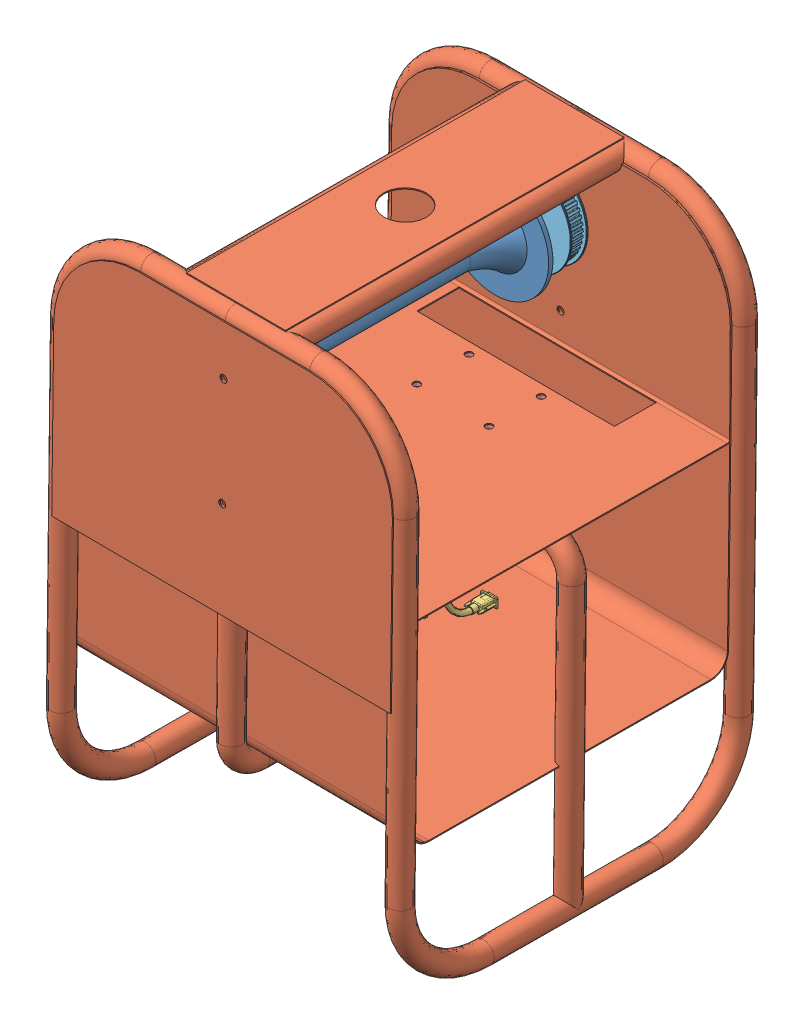
SolidWorks assembly Assem2c, configuration Default. Lengths in mm.
Overall size (326.74 509.34 328.95).
6 component instances, 6 part files, 11 mates.
Components (placement in the parent):
- mech for manipulator--1: mech for manipulator- [Default] at (-39.806 157.4104 77.9153) x (-0.943968 0.330031 -0.001958) z (0.000036 0.006038 0.999982) size (96.52 96.52 282.19)
- Robot_Chassis 1-1: Robot_Chassis 1 [Default] at (-40.8705 -18.8948 220.3334) x (0.000036 0.006038 0.999982) z (0.006038 0.999964 -0.006038) size (325.88 323.85 477.27)
- 23HS45-4204D-E1000-MC-1: 23HS45-4204D-E1000-MC [Default] at (-40.796 -6.4542 236.4495) x (-0.999982 0.006037 -0.000036) z (0 -0.006038 -0.999982) size (57.01 145.68 152.5)
- Part5-1: Part5 [Default] at (-0.507 40.5924 121.5634) x (-0.999982 0.006037 -0.000036) z (0 -0.006038 -0.999982) size (80 90 63.17)
- 3563N32_XL Series Lightweight Timing Belt Pulley-1: 3563N32_XL Series Lightweight Timing Belt Pulley [3563N32] at (-39.805 157.5811 106.197) x (-0.590425 -0.807077 0.004894) z (-0.000036 -0.006038 -0.999982) size (83.31 83.31 22.1)
- 3563N22_XL Series Lightweight Timing Belt Pulley-1: 3563N22_XL Series Lightweight Timing Belt Pulley [3563N22] at (-40.796 -7.2281 108.2629) x (0.907114 0.420877 -0.002541) z (0 -0.006038 -0.999982) size (44.45 44.45 22.1)
Mates (geometry in assembly coordinates):
- Coincident6: coincident anti-aligned: circle of mech for manipulator--1
- Parallel1: parallel anti-aligned: plane of 23HS45-4204D-E1000-MC-1 through (-69.1234 21.5346 123.2785) normal (0.006038 0.999964 -0.006038); plane of Part5-1 through (-80.5247 38.2627 181.5785) normal (-0.006038 -0.999964 0.006038)
- Parallel2: parallel anti-aligned: plane of 23HS45-4204D-E1000-MC-1 through (-40.796 -7.1461 121.8516) normal (0 -0.006038 -0.999982); plane of Part5-1 through (-0.507 40.5924 121.5634) normal (0 0.006038 0.999982)
- Tangent1: tangent anti-aligned: cylinder of 23HS45-4204D-E1000-MC-1 through (-64.2232 16.575 123.3084) axis (0 -0.006038 -0.999982) radius 2.55; plane of Part5-1 through (-66.728 24.043 118.4882) normal (0.999982 -0.006037 0.000036)
- Coincident7: coincident anti-aligned: plane of 23HS45-4204D-E1000-MC-1 through (-40.796 -7.1461 121.8516) normal (0 -0.006038 -0.999982); plane of Part5-1 through (-0.507 40.5924 121.5634) normal (0 0.006038 0.999982)
- Concentric2: concentric aligned: cylinder of mech for manipulator--1 through (-39.7957 159.1141 360.1041) axis (-0.000036 -0.006038 -0.999982) radius 6.35; cylinder of 3563N32_XL Series Lightweight Timing Belt Pulley-1 through (-39.8054 157.5144 95.1482) axis (-0.000036 -0.006038 -0.999982) radius 6.0058
- Concentric3: concentric anti-aligned: cylinder of 23HS45-4204D-E1000-MC-1 through (-40.796 -7.2632 102.452) axis (0 0.006038 0.999982) radius 4; cylinder of 3563N22_XL Series Lightweight Timing Belt Pulley-1 through (-40.796 -7.2949 97.2141) axis (0 -0.006038 -0.999982) radius 4.0069
- Distance1: distance = 2.54 mm anti-aligned: plane of 23HS45-4204D-E1000-MC-1 through (-40.796 -7.1461 121.8516) normal (0 -0.006038 -0.999982); plane of 3563N22_XL Series Lightweight Timing Belt Pulley-1 through (-36.1456 -17.184 119.3722) normal (0 0.006038 0.999982)
- Width2: width anti-aligned: plane of Part5-1 through (-81.1093 -58.9402 118.9893) normal (-0.999982 0.006037 -0.000036); plane of Robot_Chassis 1-1 through (-0.507 40.5732 118.3884) normal (0.999982 -0.006037 0.000036); plane of Part5-1 through (-129.4062 40.8674 80.286) normal (0.999982 -0.006037 0.000036); plane of Robot_Chassis 1-1 through (48.3906 39.7939 80.2924) normal (-0.999982 0.006037 -0.000036)
- Coincident14: coincident: point of Robot_Chassis 1-1; plane of Part5-1 through (-0.507 40.5732 118.3884) normal (0 -0.006038 -0.999982)
- Coincident15: coincident anti-aligned: plane of Robot_Chassis 1-1 through (111.8858 39.6646 80.2909) normal (-0.006038 -0.999964 0.006038); plane of Part5-1 through (-0.507 40.5732 118.3884) normal (0.006038 0.999964 -0.006038)
